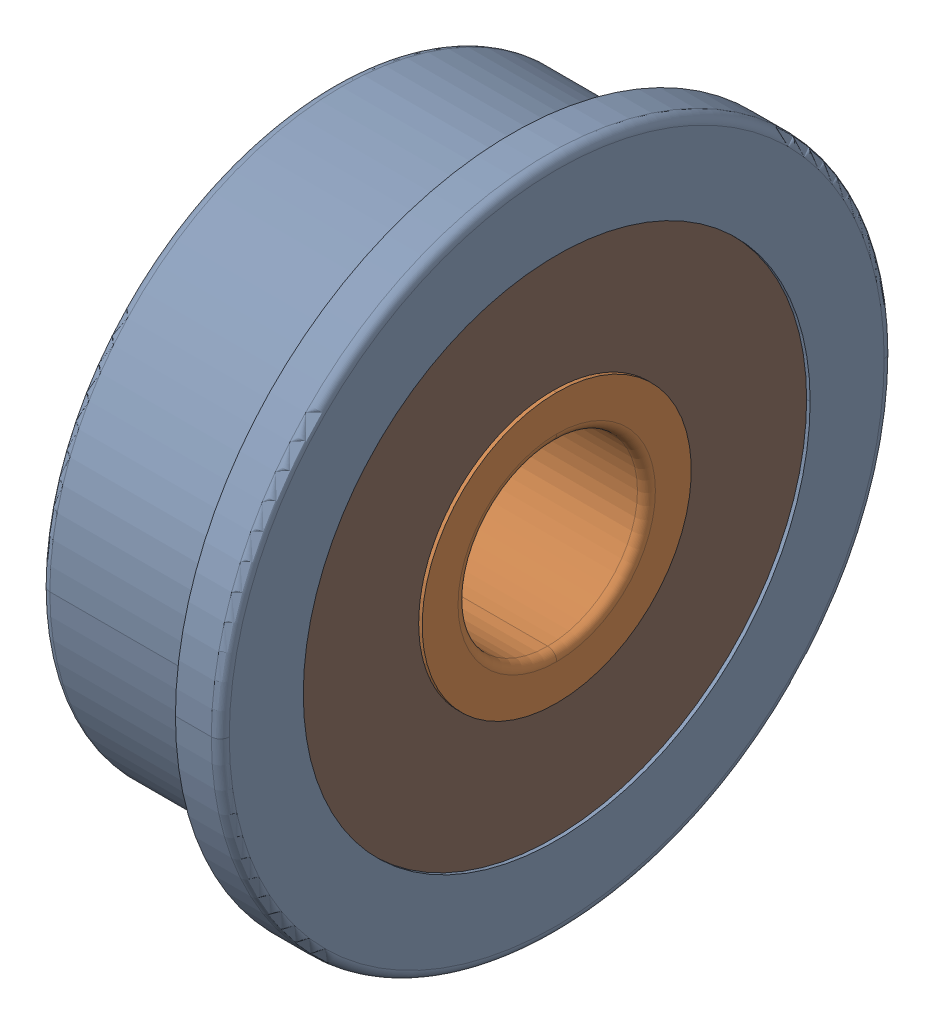
SolidWorks assembly F624ZZ, configuration Default. Lengths in mm.
Overall size (5 15 15).
11 component instances, 5 part files, 0 mates.
Components (placement in the parent):
- _F624ZZ_Outer_Ring_2-1: _F624ZZ_Outer_Ring_2 [Default] at origin size (5 15 15)
- _F624ZZ_Inner_Ring_4-1: _F624ZZ_Inner_Ring_4 [Default] x (1 0 0) z (0 -1 0) size (5 6.95 6.95)
- _F624ZZ_Shield1_6-1: _F624ZZ_Shield1_6 [Default] at (0.625 0 0) x (-1 0 0) z (0 -1 0) size (0.23 11.3 11.3)
- _F624ZZ_Ball_8-1: _F624ZZ_Ball_8 [Default] at (2.5 0 4.25) x (1 0 0) z (0 -1 0) size (2.7 2.7 2.7)
- _F624ZZ_Ball_8-2: _F624ZZ_Ball_8 [Default] at (2.5 -3.3228 2.6498) x (1 0 0) z (0 -1 0) size (2.7 2.7 2.7)
- _F624ZZ_Ball_8-3: _F624ZZ_Ball_8 [Default] at (2.5 -4.1434 -0.9457) x (1 0 0) z (0 -1 0) size (2.7 2.7 2.7)
- _F624ZZ_Ball_8-4: _F624ZZ_Ball_8 [Default] at (2.5 -1.844 -3.8291) x (1 0 0) z (0 -1 0) size (2.7 2.7 2.7)
- _F624ZZ_Ball_8-5: _F624ZZ_Ball_8 [Default] at (2.5 1.844 -3.8291) x (1 0 0) z (0 -1 0) size (2.7 2.7 2.7)
- _F624ZZ_Ball_8-6: _F624ZZ_Ball_8 [Default] at (2.5 4.1434 -0.9457) x (1 0 0) z (0 -1 0) size (2.7 2.7 2.7)
- _F624ZZ_Ball_8-7: _F624ZZ_Ball_8 [Default] at (2.5 3.3228 2.6498) x (1 0 0) z (0 -1 0) size (2.7 2.7 2.7)
- _F624ZZ_Shield2_16-1: _F624ZZ_Shield2_16 [Default] at origin size (0.23 11.3 11.3)
